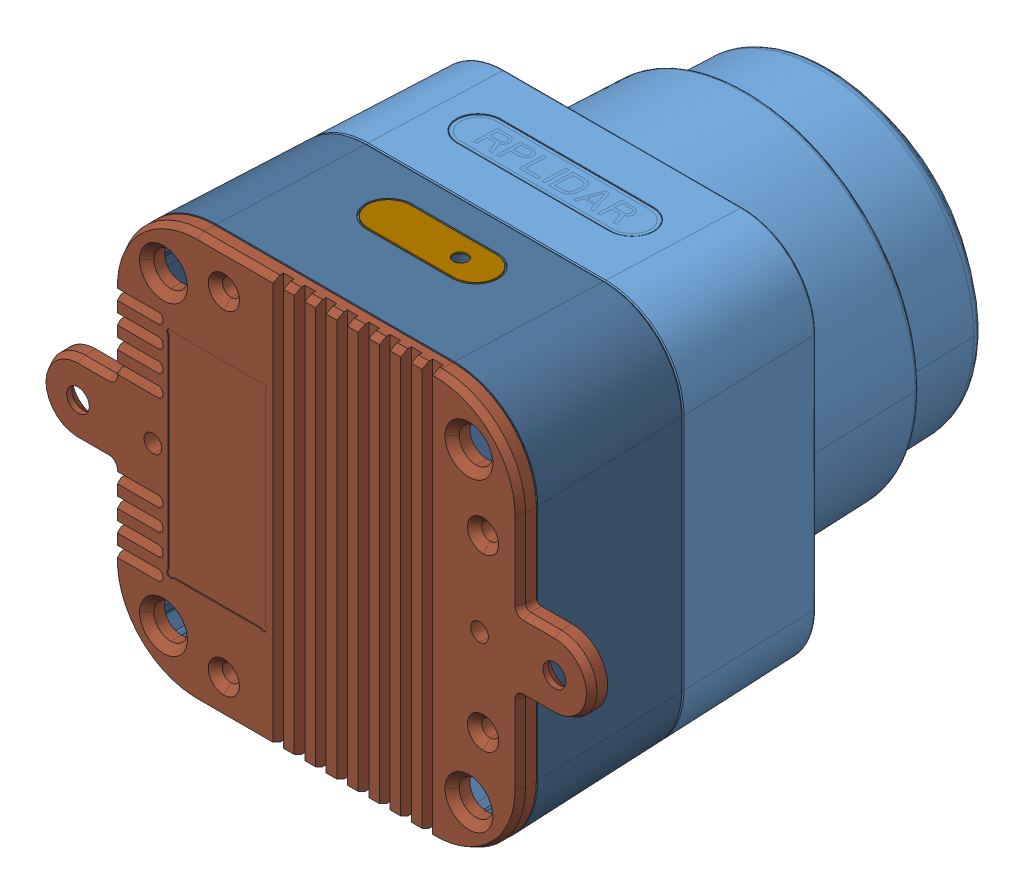
SolidWorks assembly SLAMTEC MAPPER M2M1_IGS, configuration 預設. Lengths in mm.
Overall size (97.23 108.71 74.91).
13 component instances, 12 part files, 0 mates.
Components (placement in the parent):
- SLAMTEC MAPPER M2M1_IGS(2)^SLAMTEC MAPPER M2M1_IGS-1: SLAMTEC MAPPER M2M1_IGS(2)^SLAMTEC MAPPER M2M1_IGS [預設] at origin size (97.23 108.71 74.91) (virtual)
  - rplidar-s1m1-r1^SLAMTEC MAPPER M2M1_IGS(2)_SLAMTEC MAPPER M2M1_IGS-1: rplidar-s1m1-r1^SLAMTEC MAPPER M2M1_IGS(2)_SLAMTEC MAPPER M2M1_IGS [預設] at origin size (97.23 108.71 51.5) (virtual)
  - 厙釐曹揤 ^SLAMTEC MAPPER M2M1_IGS(2)_SLAMTEC MAPPER M2M1_IGS-1: 厙釐曹揤 ^SLAMTEC MAPPER M2M1_IGS(2)_SLAMTEC MAPPER M2M1_IGS [預設] at (-6.25 -5.803 2.75) x (0 1 0) z (0 0 1) size (12.81 9.31 5.66) (virtual)
  - DC脣釱^SLAMTEC MAPPER M2M1_IGS(2)_SLAMTEC MAPPER M2M1_IGS-1: DC脣釱^SLAMTEC MAPPER M2M1_IGS(2)_SLAMTEC MAPPER M2M1_IGS [預設] at (-21.55 9.972 13.335) x (0 -1 0) z (-1 0 0) size (7.16 11.96 12.25) (virtual)
  - User Library-JST - SM06B-SRSS-TB (SH SERIES - 1_0mm PITCH WIRE-TO-BOARD, SMT, RA)^SLAMTEC MAPPER M2M1_IGS(2)_SLAMTEC MAPPER M2M1_IGS-1: User Library-JST - SM06B-SRSS-TB (SH SERIES - 1_0mm PITCH WIRE-TO-BOARD, SMT, RA)^SLAMTEC MAPPER M2M1_IGS(2)_SLAMTEC MAPPER M2M1_IGS [預設] at (0 -23.25 9.4) x (1 0 0) z (0 -1 0) size (8.81 3.31 4.96) (virtual)
  - User Library-JST - SM04B-SRSS-TB (SH SERIES - 1_0mm PITCH WIRE-TO-BOARD, SMT, RA)^SLAMTEC MAPPER M2M1_IGS(2)_SLAMTEC MAPPER M2M1_IGS-1: User Library-JST - SM04B-SRSS-TB (SH SERIES - 1_0mm PITCH WIRE-TO-BOARD, SMT, RA)^SLAMTEC MAPPER M2M1_IGS(2)_SLAMTEC MAPPER M2M1_IGS [預設] at (9.8 -23.25 9.4) x (1 0 0) z (0 -1 0) size (6.91 3.31 4.96) (virtual)
  - 綻蟯邧伎LED^SLAMTEC MAPPER M2M1_IGS(2)_SLAMTEC MAPPER M2M1_IGS-1: 綻蟯邧伎LED^SLAMTEC MAPPER M2M1_IGS(2)_SLAMTEC MAPPER M2M1_IGS [預設] at (-4 23.52 7.9) x (1 0 0) z (0 1 0) size (3.21 1.01 1.49) (virtual)
  - RJ45 1X1 SMT 8P8C-B脣釱 LCP窪遠悵__J17 DJ^SLAMTEC MAPPER M2M1_IGS(2)_SLAMTEC MAPPER M2M1_IGS-1: RJ45 1X1 SMT 8P8C-B脣釱 LCP窪遠悵__J17 DJ^SLAMTEC MAPPER M2M1_IGS(2)_SLAMTEC MAPPER M2M1_IGS [預設] at (-12.775 2.597 6.35) x (0 -1 0) z (0 0 -1) size (18.41 15.1 11.62) (virtual)
  - K2-1823SA葩弇羲壽^SLAMTEC MAPPER M2M1_IGS(2)_SLAMTEC MAPPER M2M1_IGS-1: K2-1823SA葩弇羲壽^SLAMTEC MAPPER M2M1_IGS(2)_SLAMTEC MAPPER M2M1_IGS [預設] at (4 23.75 7.1) x (-1 0 0) z (0 0 1) size (4.01 3.21 1.81) (virtual)
  - BAT_COVER1^SLAMTEC MAPPER M2M1_IGS(2)_SLAMTEC MAPPER M2M1_IGS-1: BAT_COVER1^SLAMTEC MAPPER M2M1_IGS(2)_SLAMTEC MAPPER M2M1_IGS [預設] at (0 -0.1187 -3.4) x (1 0 0) z (0 1 0) size (18.02 6.02 0.42) (virtual)
  - Mapper2-奻褲^SLAMTEC MAPPER M2M1_IGS(2)_SLAMTEC MAPPER M2M1_IGS-1: Mapper2-奻褲^SLAMTEC MAPPER M2M1_IGS(2)_SLAMTEC MAPPER M2M1_IGS [預設] x (1 0 0) z (0 1 0) size (57.05 23.13 57.05) (virtual)
  - MP2-底板-1031^SLAMTEC MAPPER M2M1_IGS(2)_SLAMTEC MAPPER M2M1_IGS-1: MP2-底板-1031^SLAMTEC MAPPER M2M1_IGS(2)_SLAMTEC MAPPER M2M1_IGS [預設] at (0 0 -1.6) x (1 0 0) z (0 1 0) size (77.12 5.51 57) (virtual)
  - Thermal pad_pad^SLAMTEC MAPPER M2M1_IGS(2)_SLAMTEC MAPPER M2M1_IGS-1: Thermal pad_pad^SLAMTEC MAPPER M2M1_IGS(2)_SLAMTEC MAPPER M2M1_IGS [預設] at (2 2.4517 21.4) x (-1 0 0) z (0 1 0) size (24.01 1.76 15.01) (virtual)
